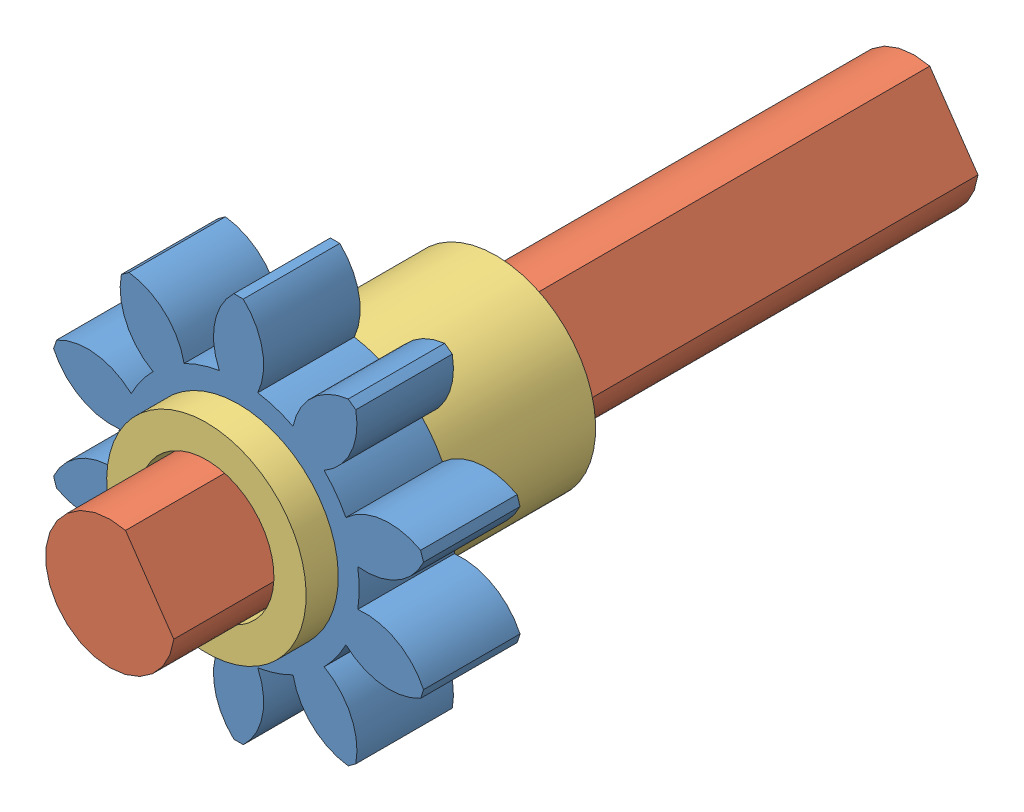
SolidWorks assembly SubAsmNum1, configuration Default. Lengths in mm.
Overall size (11.5 12 25).
4 component instances, 3 part files, 7 mates.
Components (placement in the parent):
- root_gear.-1: root_gear. [10T 1.0 Mod] at (2.8997 6.6198 8.3017) size (11.5 12 3)
- GearboxAxle-1: GearboxAxle [25mm] at (2.8997 6.6198 -9.6983) x (0.926974 -0.375125 0) z (0 0 1) size (4 3.98 25)
- GearboxSpacer-1: GearboxSpacer [4.2mm ID] at (2.8997 6.6198 3.3017) x (0.851927 0.523661 0) z (0 0 1) size (6.2 6.2 5)
- GearboxSpacer-2: GearboxSpacer [4.2 ID 1mm] at (2.8997 6.6198 12.3017) x (-0.923728 -0.383049 0) z (0 0 -1) size (6.2 6.2 1)
Mates (geometry in assembly coordinates):
- Coincident1: coincident anti-aligned: plane of root_gear.-1 through (4.8853 6.38 8.3017) normal (-0.823876 -0.56677 0); plane of GearboxAxle-1 through (3.3857 8.5598 15.3017) normal (0.823876 0.56677 0)
- Concentric1: concentric anti-aligned: cylinder of root_gear.-1 through (2.8997 6.6198 8.3017) axis (0 0 1) radius 2; cylinder of GearboxAxle-1 through (2.8997 6.6198 15.3017) axis (0 0 -1) radius 2
- Coincident2: coincident anti-aligned: plane of root_gear.-1 through (2.8997 6.6198 11.3017) normal (0 0 1); plane of GearboxSpacer-2 through (2.8997 6.6198 11.3017) normal (0 0 -1)
- Concentric2: concentric anti-aligned: cylinder of GearboxAxle-1 through (2.8997 6.6198 15.3017) axis (0 0 -1) radius 2; cylinder of GearboxSpacer-2 through (2.8997 6.6198 11.3017) axis (0 0 1) radius 2.1
- Concentric3: concentric aligned: cylinder of GearboxAxle-1 through (2.8997 6.6198 15.3017) axis (0 0 -1) radius 2; cylinder of GearboxSpacer-1 through (2.8997 6.6198 8.3017) axis (0 0 -1) radius 2.1
- Coincident3: coincident anti-aligned: plane of root_gear.-1 through (2.8997 6.6198 8.3017) normal (0 0 -1); plane of GearboxSpacer-1 through (2.8997 6.6198 8.3017) normal (0 0 1)
- Distance1: distance = 3 mm aligned: plane of GearboxSpacer-2 through (2.8997 6.6198 12.3017) normal (0 0 1); plane of GearboxAxle-1 through (2.8997 6.6198 15.3017) normal (0 0 1)
